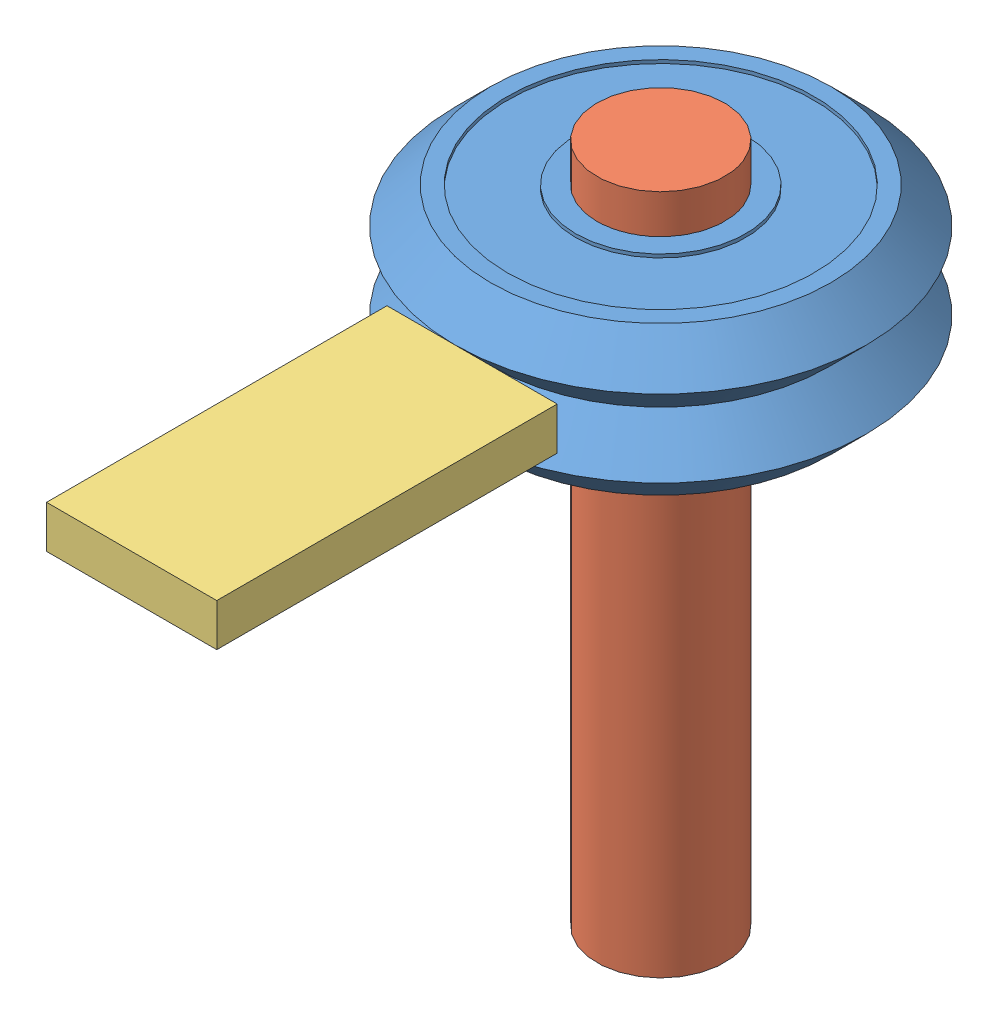
SolidWorks assembly VBearingAssembly, configuration Default. Lengths in mm.
Overall size (30.73 50.8 54.84).
3 component instances, 3 part files, 5 mates.
Components (placement in the parent):
- VGroove Bearing-1: VGroove Bearing [Rev 1.1] at (10.3505 15.8506 24.3054) size (30.73 11.1 30.73)
- VGrooveBearingBolt-1: VGrooveBearingBolt [Default] at (10.3505 -26.4976 24.3054) x (0.968252 0 -0.249975) z (0 1 0) size (9.53 9.53 50.8)
- Part3^VBearingAssembly-1: Part3^VBearingAssembly [Default] at (16.7007 17.4381 38.3829) x (0 -1 0) z (-1 0 0) size (3.17 25.4 12.7) (virtual)
Mates (geometry in assembly coordinates):
- Concentric1: concentric anti-aligned: cylinder of VGroove Bearing-1 through (10.3505 80.2404 24.3054) axis (0 1 0) radius 4.7625; cylinder of VGrooveBearingBolt-1 through (10.3505 24.3024 24.3054) axis (0 -1 0) radius 4.7625
- Parallel1: parallel aligned: plane of VGroove Bearing-1 through (15.113 21.4006 24.3054) normal (0 1 0); plane of Part3^VBearingAssembly-1 through (4.0007 17.4381 38.3829) normal (0 1 0)
- Width1: width aligned: plane of VGroove Bearing-1 through (15.113 21.4006 24.3054) normal (0 1 0); plane of VGroove Bearing-1 through (23.0405 10.3006 24.3054) normal (0 -1 0); plane of Part3^VBearingAssembly-1 through (4.0007 17.4381 38.3829) normal (0 1 0); plane of Part3^VBearingAssembly-1 through (4.0007 14.2631 38.3829) normal (0 -1 0)
- Coincident5: coincident: cone of VGroove Bearing-1 through (10.3505 18.7256 24.3054) axis (0 -1 0); moEndPointRef_w of Part3^VBearingAssembly-1
- Parallel4: parallel anti-aligned: plane of Part3^VBearingAssembly-1 through (4.0007 17.4381 38.3829) normal (-1 0 0); plane of assembly through (0 0 0) normal (1 0 0)
